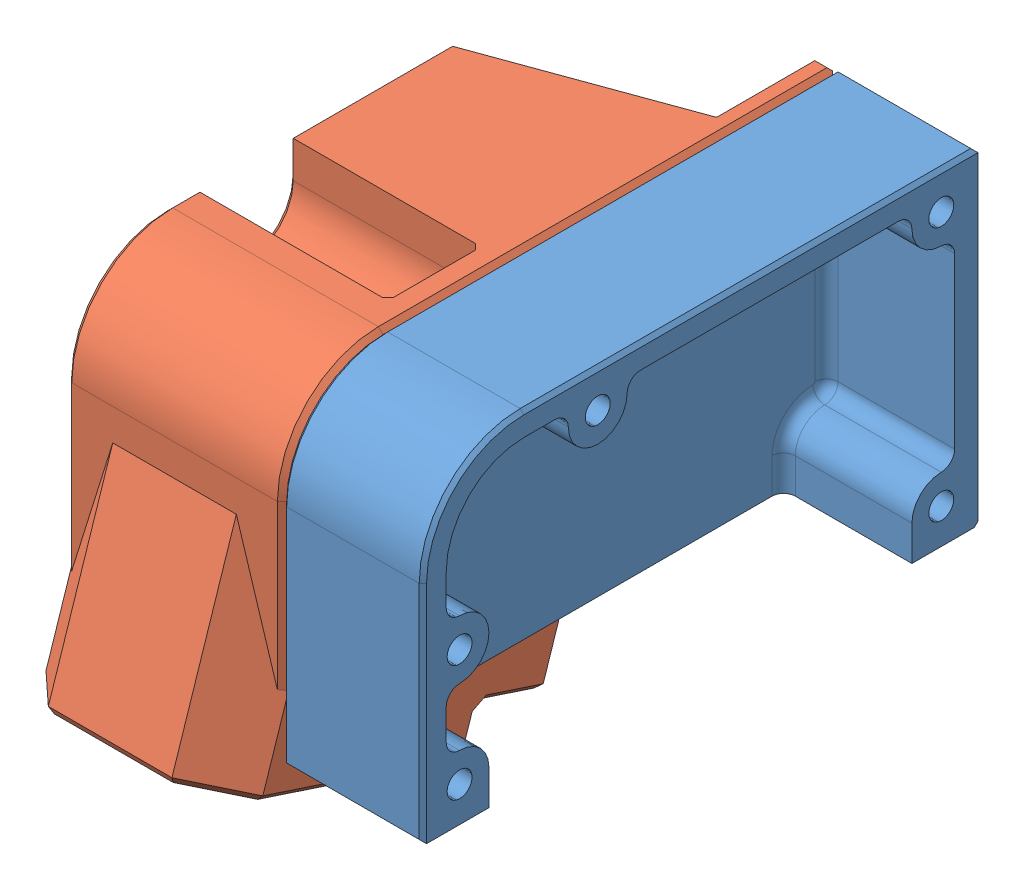
SolidWorks assembly Left Damper Debris Shield, configuration Default. Lengths in mm.
Overall size (48.58 60.12 84.36).
2 component instances, 2 part files, 4 mates.
Components (placement in the parent):
- Left Damper Debris Shield Spacer-1: Left Damper Debris Shield Spacer [Default] at origin size (19.05 44.45 75.59)
- Left Damper Debris Shield Top Plate-1: Left Damper Debris Shield Top Plate [Default] at origin size (29.53 60.12 84.36)
Mates (geometry in assembly coordinates):
- InPlace1: in place: plane of ? through (0 19.3857 -6.3737) normal (0 -0.949972 0.312335); plane of ? through (0 19.3857 -6.3737) normal (0 -0.949972 0.312335); moOrthogonalPlaneRef_w of ? through (0 19.3857 -6.3737) normal (0 -0.949972 0.312335); plane of ? through (0 19.3857 -6.3737) normal (0 -0.312335 -0.949972); plane of ? through (0 19.3857 -6.3737) normal (0 -0.949972 0.312335); plane of ? through (0 19.3857 -6.3737) normal (-1 0 0); plane of ? through (0 19.3857 -6.3737) normal (0 -0.949972 0.312335); unknown of ?
- Coincident1: coincident aligned: plane of Left Damper Debris Shield Top Plate-1; plane of ?
- Coincident2: coincident aligned: moOrthogonalPlaneRef_w of Left Damper Debris Shield Top Plate-1 through (0 19.3857 -6.3737) normal (0 -0.312335 -0.949972); plane of Part8^Left Damper Debris Shield-1 through (0 37.8112 3.3413) normal (0 0.088025 -0.996118)
- Coincident3: coincident anti-aligned: moOrthogonalPlaneRef_w of Left Damper Debris Shield Top Plate-1 through (0 19.3857 -6.3737) normal (1 0 0); plane of Part8^Left Damper Debris Shield-1 through (0 37.8112 3.3413) normal (-1 0 0)
